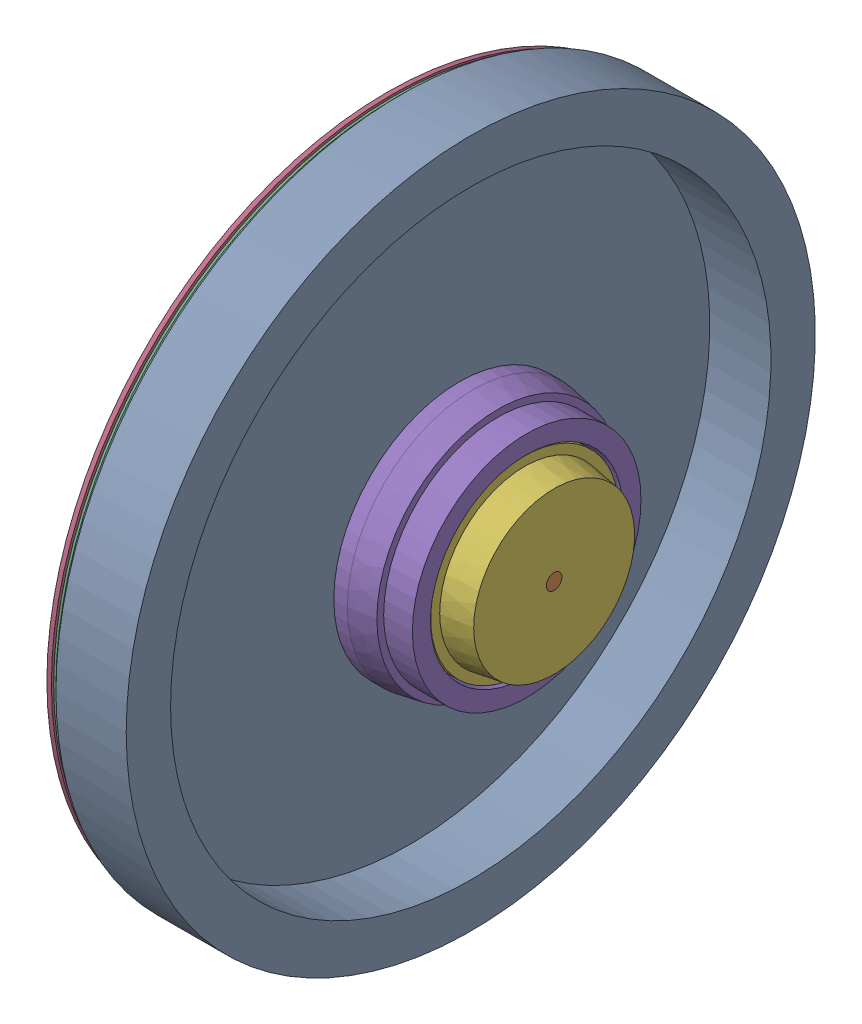
SolidWorks assembly 03_Turntable, configuration Default. Lengths in mm.
Overall size (81.31 304 304).
7 component instances, 6 part files, 0 mates.
Components (placement in the parent):
- Turntable-1: Turntable [Default] at origin size (33 304 304)
- Axle-1: Axle [Default] at origin size (81.31 6.86 6.86)
- Mat-1: Mat [Default] at (890.3949 482.5 -406.8949) x (0 0 1) z (0 -1 0) size (300 2 300)
- MusicDisc-1: MusicDisc [Default] at (522.2252 -15.5 176) x (0 0 -1) z (1 0 0) size (300 300 2)
- Drive-1: Drive [Default] at (28 157.5 157.5) x (1 0 0) z (0 1 0) size (52.77 110.86 110.86)
  - Motor_Rotor-1: Motor_Rotor [Default] at (0 157.5 -157.5) x (1 0 0) z (0 -1 0) size (40.67 110.86 110.86)
  - Motor_Stator-1: Motor_Stator [Default] at (0 157.5 -157.5) x (1 0 0) z (0 -1 0) size (29.77 82.97 82.97)
